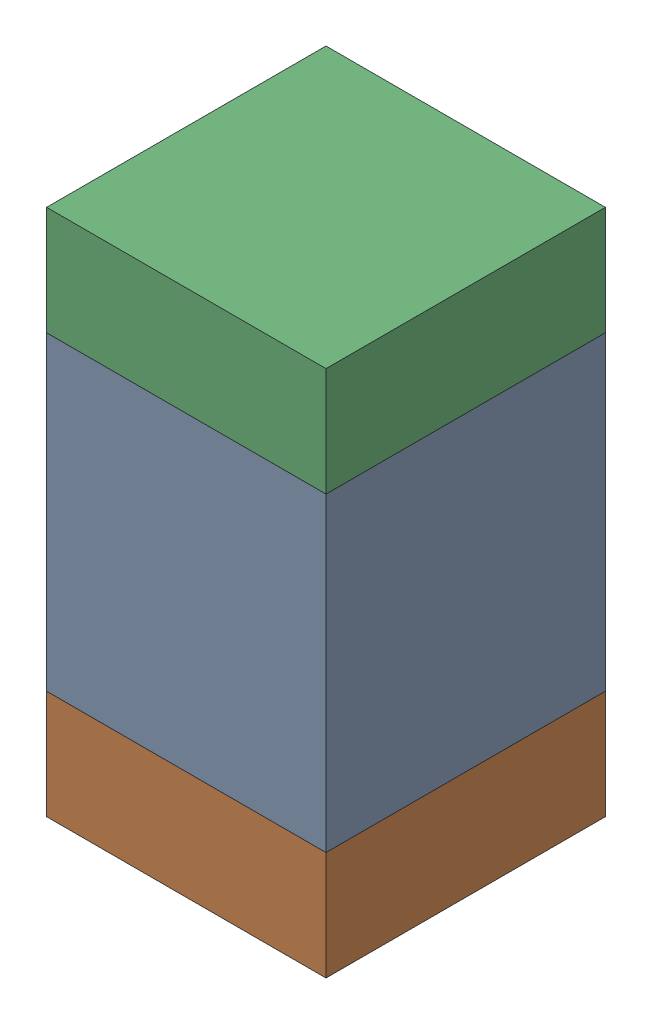
SolidWorks assembly C3, configuration Default. Lengths in mm.
Overall size (0.9 1.7 0.9).
6 component instances, 2 part files, 0 mates.
Components (placement in the parent):
- 5613956208-1: 5613956208 [Default] at (136.5 83.8 -2.5914) size (0.9 1 0.9)
  - Extruded_2-1: Extruded_2 [Default] at origin size (0.9 1 0.9)
- 5613953728-1: 5613953728 [Default] at (136.5 83.125 -2.5914) size (0.9 0.35 0.9)
  - Extruded_8-1: Extruded_8 [Default] at origin size (0.9 0.35 0.9)
- 5613953728-2: 5613953728 [Default] at (136.5 84.475 -2.5914) size (0.9 0.35 0.9)
  - Extruded_8-1: Extruded_8 [Default] at origin size (0.9 0.35 0.9)
